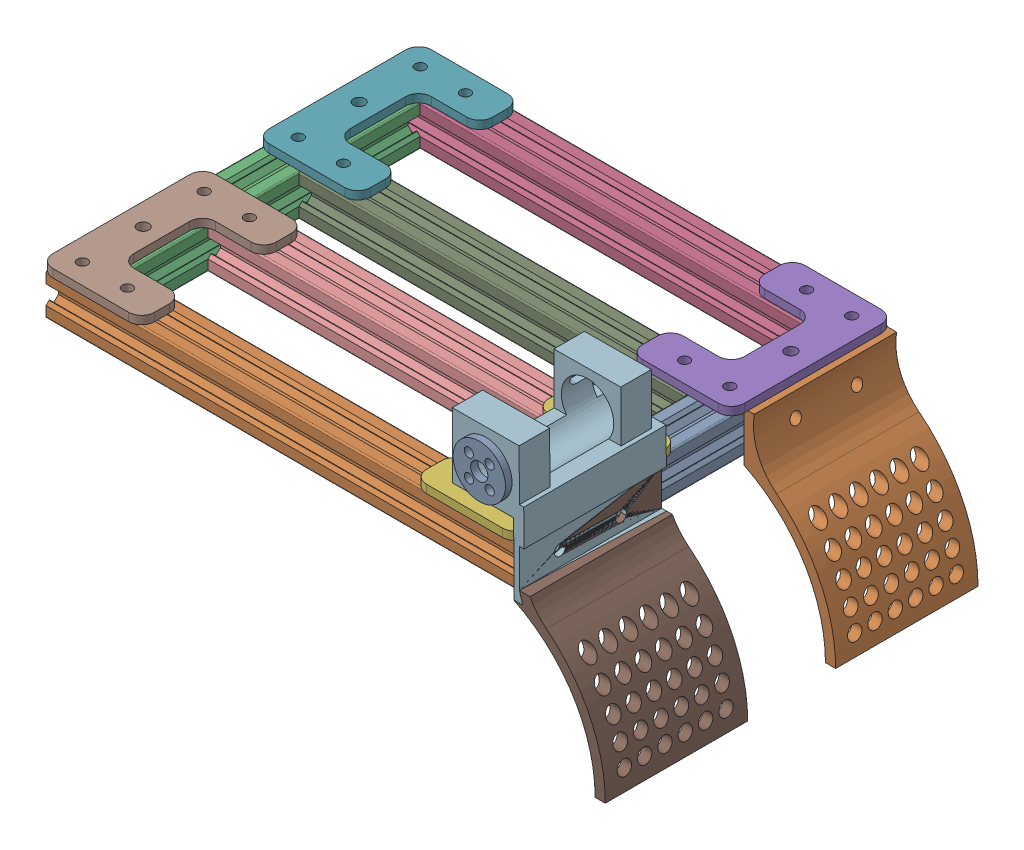
SolidWorks assembly EnsambleEstructuraArriba, configuration Predeterminado. Lengths in mm.
Overall size (276.86 131.02 188.36).
12 component instances, 6 part files, 15 mates.
Components (placement in the parent):
- Perfil_paredes2_-1: Perfil_paredes2_ [Predeterminado] at (-16.8498 1.8452 -2.9916) size (20 20 144)
- Perfil_paredes_-2: Perfil_paredes_ [Predeterminado] at (-236.8498 1.8452 151.0084) x (0 0 -1) z (1 0 0) size (20 20 230)
- Perfil_paredes2_-2: Perfil_paredes2_ [Predeterminado] at (-226.8498 1.8452 -2.9916) size (20 20 144)
- Perfil_paredes_-3: Perfil_paredes_ [Predeterminado] at (-236.8498 1.8452 -12.9916) x (0 0 -1) z (1 0 0) size (20 20 230)
- pieza soporte H2-1: pieza soporte H2 [Predeterminado] at (-31.5943 15.8452 56.0866) x (0 0 -1) z (0 -1 0) size (80 50 4)
- pieza soporte H2-2: pieza soporte H2 [Predeterminado] at (-31.5943 15.8452 162.3063) x (0 0 -1) z (0 -1 0) size (80 50 4)
- pieza soporte H2-3: pieza soporte H2 [Predeterminado] at (-212.1053 15.8452 -24.2895) x (0 0 1) z (0 -1 0) size (80 50 4)
- pieza soporte H2-4: pieza soporte H2 [Predeterminado] at (-212.1053 15.8452 81.9302) x (0 0 1) z (0 -1 0) size (80 50 4)
- Perfil_paredes_1-3: Perfil_paredes_1 [Predeterminado] at (-216.8498 1.8452 46.6485) x (0 0 -1) z (1 0 0) size (20 20 190)
- Perfil_paredes_1-4: Perfil_paredes_1 [Predeterminado] at (-216.8498 1.8452 91.3683) x (0 0 -1) z (1 0 0) size (20 20 190)
- OR_Sopor_Bump-3: OR_Sopor_Bump [Default] at (54.5901 -72.4327 116.0738) x (0 0 1) z (-1 0 0) size (73.25 131.02 75.26)
- OR_Bumper-1: OR_Bumper [Predeterminado] at (18.344 -41.3499 -22.2416) x (0 0 1) z (-1 0 0) size (70 88.26 45)
Mates (geometry in assembly coordinates):
- Coincidente3: coincident: point of Perfil_paredes2_-1; point of Perfil_paredes_-2
- Coincidente4: coincident: point of Perfil_paredes_-2; point of Perfil_paredes2_-2
- Coincidente5: coincident: point of Perfil_paredes2_-1; point of Perfil_paredes_-3
- Coincidente6: coincident: unknown of Perfil_paredes_-2; moEndPointRef_w of pieza soporte H2-4
- Coincidente7: coincident: plane of Perfil_paredes_-3 through (-236.8498 11.0952 -3.7416) normal (-1 0 0); unknown of pieza soporte H2-3
- Coincidente9: coincident: unknown of Perfil_paredes_-2; unknown of pieza soporte H2-2
- Coincidente10: coincident: unknown of Perfil_paredes_-3; unknown of pieza soporte H2-1
- Coincidente14: coincident: line of Perfil_paredes_-3 through (-6.8498 11.8452 -22.2416) axis (-1 0 0); unknown of pieza soporte H2-3
- Coincidente16: coincident anti-aligned: plane of Perfil_paredes2_-1 through (-26.8498 6.4452 141.0084) normal (-1 0 0); plane of Perfil_paredes_1-3 through (-26.8498 11.0952 55.8985) normal (1 0 0)
- Coincidente18: coincident anti-aligned: plane of Perfil_paredes2_-1 through (-26.8498 6.4452 141.0084) normal (-1 0 0); plane of Perfil_paredes_1-4 through (-26.8498 11.0952 100.6183) normal (1 0 0)
- Coincidente20: coincident: circle of Perfil_paredes_-3; point of Sopor_Bump_-1
- Coincidente21: coincident: point of Perfil_paredes_-2; point of Bumper (1)-1
- Coincidente22: coincident: point of Perfil_paredes_-3; point of Bumper (1)-2
- Coincidente23: coincident: point of Perfil_paredes_-2; point of Sopor_Bump_-3
- Coincidente24: coincident: point of Perfil_paredes_-3; point of OR_Bumper-1
